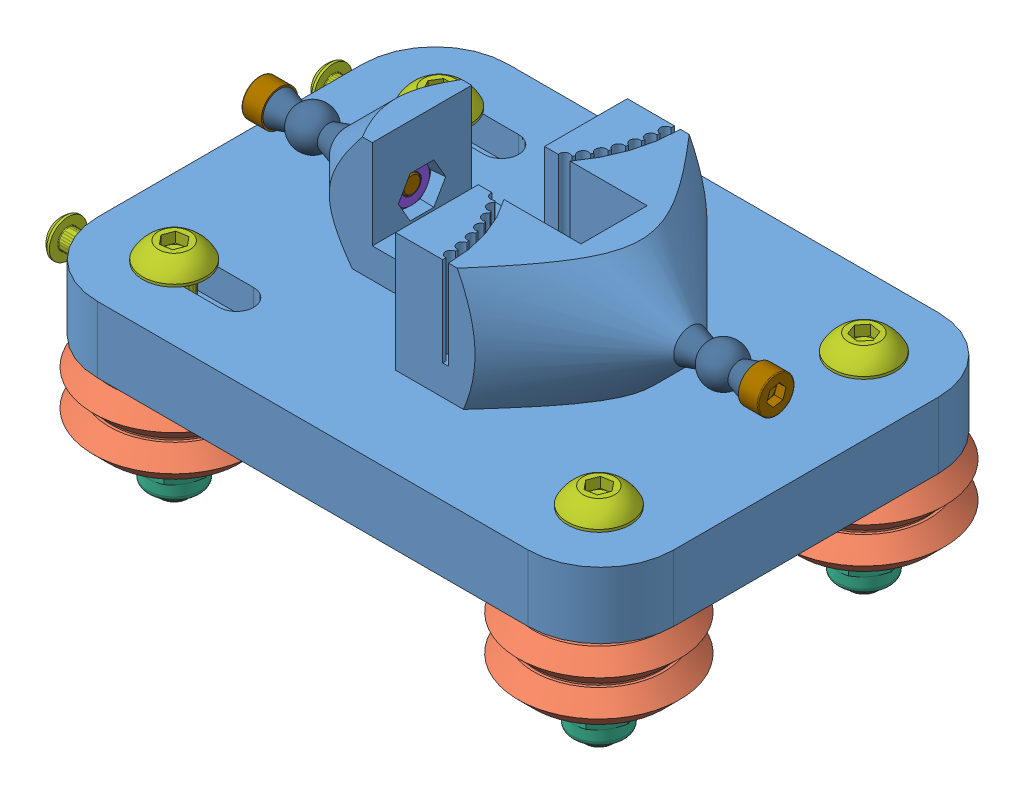
SolidWorks assembly Carriage, configuration Default. Lengths in mm.
Overall size (98.62 48 70.21).
43 component instances, 10 part files, 52 mates.
Components (placement in the parent):
- Carriage Plate-1: Carriage Plate [Default] at (-68.6928 -3.4221 37.1074) size (87 28 62)
- Dual V Wheel Assy-1: Dual V Wheel Assy [Default] at (-5.296 -57.3171 -30.5998) x (0 -1 0) z (0.099606 0 0.995027) size (17.35 24.39 24.39)
  - Dual V Wheel-1: Dual V Wheel [Default] at (-47.445 10.5779 17.8496) size (10.23 24.39 24.39)
  - 625 2RS-1: 625 2RS [Default] at (-46.945 10.5779 17.8496) x (0 0 1) z (-1 0 0) size (16 16 5)
  - 625 2RS-2: 625 2RS [Default] at (-52.945 10.5779 17.8496) x (0 -0.999394 0.034809) z (-1 0 0) size (16 16 5)
  - Precision Shim-1: Precision Shim [Default] at (-47.445 10.5779 17.8496) size (1 7.7 7.7)
  - Quarter Inch washer-1: Quarter Inch washer [Default] at (-56.12 10.5779 17.8496) x (1 0 0) z (0 -0.459208 0.888329) size (6.35 8 8)
- Dual V Wheel Assy-2: Dual V Wheel Assy [Default] at (16.2723 -57.3171 7.5423) x (0 -1 0) z (-0.840315 0 0.542098) size (17.35 24.39 24.39)
  - Dual V Wheel-1: Dual V Wheel [Default] at (-47.445 10.5779 17.8496) size (10.23 24.39 24.39)
  - 625 2RS-1: 625 2RS [Default] at (-46.945 10.5779 17.8496) x (0 0 1) z (-1 0 0) size (16 16 5)
  - 625 2RS-2: 625 2RS [Default] at (-52.945 10.5779 17.8496) x (0 -0.999394 0.034809) z (-1 0 0) size (16 16 5)
  - Precision Shim-1: Precision Shim [Default] at (-47.445 10.5779 17.8496) size (1 7.7 7.7)
  - Quarter Inch washer-1: Quarter Inch washer [Default] at (-56.12 10.5779 17.8496) x (1 0 0) z (0 -0.459208 0.888329) size (6.35 8 8)
- Dual V Wheel Assy-3: Dual V Wheel Assy [Default] at (-72.4169 -57.3171 40.1065) x (0 -1 0) z (0.978939 0 -0.204151) size (17.35 24.39 24.39)
  - Dual V Wheel-1: Dual V Wheel [Default] at (-47.445 10.5779 17.8496) size (10.23 24.39 24.39)
  - 625 2RS-1: 625 2RS [Default] at (-46.945 10.5779 17.8496) x (0 0 1) z (-1 0 0) size (16 16 5)
  - 625 2RS-2: 625 2RS [Default] at (-52.945 10.5779 17.8496) x (0 -0.999394 0.034809) z (-1 0 0) size (16 16 5)
  - Precision Shim-1: Precision Shim [Default] at (-47.445 10.5779 17.8496) size (1 7.7 7.7)
  - Quarter Inch washer-1: Quarter Inch washer [Default] at (-56.12 10.5779 17.8496) x (1 0 0) z (0 -0.459208 0.888329) size (6.35 8 8)
- Dual V Wheel Assy-4: Dual V Wheel Assy [Default] at (-68.5718 -57.3171 -31.1832) x (0 -1 0) z (0.050683 0 0.998715) size (17.35 24.39 24.39)
  - Dual V Wheel-1: Dual V Wheel [Default] at (-47.445 10.5779 17.8496) size (10.23 24.39 24.39)
  - 625 2RS-1: 625 2RS [Default] at (-46.945 10.5779 17.8496) x (0 0 1) z (-1 0 0) size (16 16 5)
  - 625 2RS-2: 625 2RS [Default] at (-52.945 10.5779 17.8496) x (0 -0.999394 0.034809) z (-1 0 0) size (16 16 5)
  - Precision Shim-1: Precision Shim [Default] at (-47.445 10.5779 17.8496) size (1 7.7 7.7)
  - Quarter Inch washer-1: Quarter Inch washer [Default] at (-56.12 10.5779 17.8496) x (1 0 0) z (0 -0.459208 0.888329) size (6.35 8 8)
- torque nut 01_iso-1: torque nut 01_iso [ISO 7040-M5-C] at (-57.1028 -19.7721 26.1074) x (0.027758 0 0.999615) z (0 -1 0) size (8 9.24 6.8)
- socket button head screw_iso-2: socket button head screw_iso [ISO 7380 - M5 x 30 --- 30C] at (-57.1028 9.3279 26.1074) x (0 -1 0) z (0.169605 0 0.985512) size (32.75 9.5 9.5)
- socket button head screw_iso-3: socket button head screw_iso [ISO 7380 - M5 x 30 --- 30C] at (7.0072 9.3279 26.1074) x (0 -1 0) z (-0.775954 0 0.63079) size (32.75 9.5 9.5)
- socket button head screw_iso-4: socket button head screw_iso [ISO 7380 - M5 x 30 --- 30C] at (7.0072 9.3279 -13.8926) x (0 -1 0) z (-0.770259 0 -0.637731) size (32.75 9.5 9.5)
- socket button head screw_iso-5: socket button head screw_iso [ISO 7380 - M5 x 30 --- 30C] at (-57.1028 9.3279 -13.8926) x (0 -1 0) z (-0.853361 0 -0.52132) size (32.75 9.5 9.5)
- torque nut 01_iso-2: torque nut 01_iso [ISO 7040-M5-C] at (7.0072 -19.7721 26.1074) x (-0.044821 0 0.998995) z (0 -1 0) size (8 9.24 6.8)
- torque nut 01_iso-3: torque nut 01_iso [ISO 7040-M5-C] at (7.0072 -19.7721 -13.8926) x (-0.103086 0 0.994672) z (0 -1 0) size (8 9.24 6.8)
- torque nut 01_iso-4: torque nut 01_iso [ISO 7040-M5-C] at (-57.1028 -19.7721 -13.8926) x (-0.974294 0 -0.225282) z (0 -1 0) size (8 9.24 6.8)
- socket button head screw_iso-6: socket button head screw_iso [ISO 7380 - M3 x 12 --- 12C] at (-74.7528 1.5779 26.1074) x (1 0 0) z (0 0.980313 0.197449) size (13.65 5.7 5.7)
- torque nut 01_iso-5: torque nut 01_iso [ISO 7040-M3-C] at (-63.5428 1.5779 26.1074) x (0 -0.866025 -0.5) z (1 0 0) size (5.5 6.35 4.5)
- socket button head screw_iso-7: socket button head screw_iso [ISO 7380 - M3 x 12 --- 12C] at (-74.7528 1.5779 -13.8926) x (1 0 0) z (0 0.265442 0.964127) size (13.65 5.7 5.7)
- torque nut 01_iso-6: torque nut 01_iso [ISO 7040-M3-C] at (-63.5428 1.5779 -13.8926) x (0 -0.866025 0.5) z (1 0 0) size (5.5 6.35 4.5)
- hex nut style 1 gradeab_iso-1: hex nut style 1 gradeab_iso [Hexagon Nut ISO - 4032 - M3 - D - C] at (-9.0928 14.5779 6.1074) x (0 -0.5 0.866025) z (-1 0 0) size (5.5 6.35 2.4)
- socket head cap screw_iso-1: socket head cap screw_iso [ISO 4762 M3 x 20 --- 20C] at (13.8072 14.5779 6.1074) x (-1 0 0) z (0 -0.980465 -0.196695) size (23 5.5 5.5)
- Traxxas Ball-1: Traxxas Ball [Default] at (0.8072 14.5779 6.1074) x (0 -1 0) z (0 0 1) size (6 10 6)
- Traxxas Ball-2: Traxxas Ball [Default] at (-61.1928 14.5779 6.1074) x (0 -1 0) z (0 0 1) size (6 10 6)
- socket head cap screw_iso-2: socket head cap screw_iso [ISO 4762 M3 x 20 --- 20C] at (-64.1928 14.5779 6.1074) x (1 0 0) z (0 -0.973692 0.227866) size (23 5.5 5.5)
- hex nut style 1 gradeab_iso-2: hex nut style 1 gradeab_iso [Hexagon Nut ISO - 4032 - M3 - D - C] at (-43.6928 14.5779 6.1074) x (0 -0.5 0.866025) z (-1 0 0) size (5.5 6.35 2.4)
Mates (geometry in assembly coordinates):
- Concentric1: concentric aligned: cylinder of Carriage Plate-1 through (7.0072 1.9779 -13.8926) axis (0 -1 0) radius 4.1; cylinder of Dual V Wheel Assy-1/Quarter Inch washer-1 through (7.0072 -1.1971 -13.8926) axis (0 -1 0) radius 4
- Distance1: distance = 0.3 mm anti-aligned: plane of Carriage Plate-1 through (-68.6928 1.6779 37.1074) normal (0 -1 0); plane of Dual V Wheel Assy-1/Quarter Inch washer-1 through (10.7259 1.9779 -12.4189) normal (0 1 0)
- Concentric2: concentric aligned: cylinder of Carriage Plate-1 through (7.0072 1.9779 26.1074) axis (0 -1 0) radius 4.1; cylinder of Dual V Wheel Assy-2/Quarter Inch washer-1 through (7.0072 -1.1971 26.1074) axis (0 -1 0) radius 4
- Distance2: distance = 0.3 mm anti-aligned: plane of Carriage Plate-1 through (-68.6928 1.6779 37.1074) normal (0 -1 0); plane of Dual V Wheel Assy-2/Quarter Inch washer-1 through (7.39 1.9779 30.089) normal (0 1 0)
- Distance6: distance = 0.1 mm anti-aligned: plane of Carriage Plate-1 through (-47.6928 1.9779 22.0074) normal (0 0 1); cylinder of Dual V Wheel Assy-3/Quarter Inch washer-1 through (-57.1028 -1.1971 26.1074) axis (0 -1 0) radius 4
- Distance3: distance = 0.3 mm anti-aligned: plane of Dual V Wheel Assy-3/Quarter Inch washer-1 through (-56.03 1.9779 22.2539) normal (0 1 0); plane of Carriage Plate-1 through (-68.6928 1.6779 37.1074) normal (0 -1 0)
- LimitDistance1: limit distance = 4.59 mm anti-aligned: cylinder of Dual V Wheel Assy-3/Quarter Inch washer-1 through (-57.1028 -1.1971 26.1074) axis (0 -1 0) radius 4; plane of Carriage Plate-1 through (-65.6928 1.9779 23.3574) normal (1 0 0)
- Distance7: distance = 0.1 mm anti-aligned: cylinder of Dual V Wheel Assy-4/Quarter Inch washer-1 through (-57.1028 -1.1971 -13.8926) axis (0 -1 0) radius 4; plane of Carriage Plate-1 through (-58.6928 1.9779 -9.7926) normal (0 0 -1)
- Distance8: distance = 0.3 mm anti-aligned: plane of Dual V Wheel Assy-4/Quarter Inch washer-1 through (-53.4609 1.9779 -12.2382) normal (0 1 0); plane of Carriage Plate-1 through (-68.6928 1.6779 37.1074) normal (0 -1 0)
- LimitDistance2: limit distance = 4.59 mm anti-aligned: cylinder of Dual V Wheel Assy-4/Quarter Inch washer-1 through (-57.1028 -1.1971 -13.8926) axis (0 -1 0) radius 4; plane of Carriage Plate-1 through (-65.6928 1.9779 -16.6426) normal (1 0 0)
- Coincident6: coincident anti-aligned: plane of Dual V Wheel Assy-3/625 2RS-1 through (-57.6438 -15.3721 23.5132) normal (0 -1 0); plane of torque nut 01_iso-1 through (-61.7198 -15.3721 26.2356) normal (0 1 0)
- Concentric7: concentric anti-aligned: cylinder of Dual V Wheel Assy-3/625 2RS-1 through (-57.1028 -10.3721 26.1074) axis (0 -1 0) radius 2.5; cylinder of socket button head screw_iso-2 through (-57.1028 9.3279 26.1074) axis (0 1 0) radius 2.5
- Coincident7: coincident anti-aligned: plane of Carriage Plate-1 through (7.3072 6.5779 -13.8926) normal (0 1 0); plane of socket button head screw_iso-2 through (-54.639 6.5779 25.6834) normal (0 -1 0)
- Concentric8: concentric anti-aligned: cylinder of torque nut 01_iso-1 through (-57.1028 -15.3721 26.1074) axis (0 -1 0) radius 2.1; cylinder of socket button head screw_iso-2 through (-57.1028 9.3279 26.1074) axis (0 1 0) radius 2.5
- Concentric9: concentric anti-aligned: cylinder of Dual V Wheel Assy-2/625 2RS-1 through (7.0072 -10.3721 26.1074) axis (0 -1 0) radius 2.5; cylinder of socket button head screw_iso-3 through (7.0072 9.3279 26.1074) axis (0 1 0) radius 2.5
- Concentric10: concentric anti-aligned: cylinder of socket button head screw_iso-3 through (7.0072 9.3279 26.1074) axis (0 1 0) radius 2.5; cylinder of torque nut 01_iso-2 through (7.0072 -15.3721 26.1074) axis (0 -1 0) radius 2.1
- Concentric11: concentric anti-aligned: cylinder of Dual V Wheel Assy-1/625 2RS-1 through (7.0072 -10.3721 -13.8926) axis (0 -1 0) radius 2.5; cylinder of socket button head screw_iso-4 through (7.0072 9.3279 -13.8926) axis (0 1 0) radius 2.5
- Concentric12: concentric anti-aligned: cylinder of socket button head screw_iso-4 through (7.0072 9.3279 -13.8926) axis (0 1 0) radius 2.5; cylinder of torque nut 01_iso-3 through (7.0072 -15.3721 -13.8926) axis (0 -1 0) radius 2.1
- Concentric13: concentric anti-aligned: cylinder of Dual V Wheel Assy-4/625 2RS-1 through (-57.1028 -10.3721 -13.8926) axis (0 -1 0) radius 2.5; cylinder of socket button head screw_iso-5 through (-57.1028 9.3279 -13.8926) axis (0 1 0) radius 2.5
- Concentric14: concentric anti-aligned: cylinder of socket button head screw_iso-5 through (-57.1028 9.3279 -13.8926) axis (0 1 0) radius 2.5; cylinder of torque nut 01_iso-4 through (-57.1028 -15.3721 -13.8926) axis (0 -1 0) radius 2.1
- Coincident8: coincident anti-aligned: plane of Carriage Plate-1 through (7.3072 6.5779 -13.8926) normal (0 1 0); plane of socket button head screw_iso-3 through (8.5842 6.5779 28.0473) normal (0 -1 0)
- Coincident9: coincident anti-aligned: plane of Carriage Plate-1 through (7.3072 6.5779 -13.8926) normal (0 1 0); plane of socket button head screw_iso-4 through (5.4129 6.5779 -11.967) normal (0 -1 0)
- Coincident10: coincident anti-aligned: plane of Carriage Plate-1 through (7.3072 6.5779 -13.8926) normal (0 1 0); plane of socket button head screw_iso-5 through (-58.4061 6.5779 -11.7592) normal (0 -1 0)
- Coincident11: coincident anti-aligned: plane of Dual V Wheel Assy-2/625 2RS-1 through (8.4438 -15.3721 28.3342) normal (0 -1 0); plane of torque nut 01_iso-2 through (2.3931 -15.3721 25.9004) normal (0 1 0)
- Coincident12: coincident anti-aligned: plane of Dual V Wheel Assy-1/625 2RS-1 through (9.6441 -15.3721 -14.1566) normal (0 -1 0); plane of torque nut 01_iso-3 through (2.4131 -15.3721 -14.3687) normal (0 1 0)
- Coincident13: coincident anti-aligned: plane of Dual V Wheel Assy-4/625 2RS-1 through (-54.4562 -15.3721 -14.0269) normal (0 -1 0); plane of torque nut 01_iso-4 through (-56.0622 -15.3721 -18.3927) normal (0 1 0)
- Concentric15: concentric aligned: cylinder of Carriage Plate-1 through (18.3082 1.5779 26.1074) axis (-1 0 0) radius 1.6; cylinder of socket button head screw_iso-6 through (-74.7528 1.5779 26.1074) axis (-1 0 0) radius 1.5
- LimitDistance3: limit distance = 4.41 mm anti-aligned: plane of socket button head screw_iso-6 through (-73.1028 1.8741 24.6369) normal (1 0 0); plane of Carriage Plate-1 through (-68.6928 6.5779 26.1074) normal (-1 0 0)
- Concentric16: concentric anti-aligned: cylinder of socket button head screw_iso-6 through (-74.7528 1.5779 26.1074) axis (-1 0 0) radius 1.5; cylinder of torque nut 01_iso-5 through (-65.6928 1.5779 26.1074) axis (1 0 0) radius 1.25
- Coincident15: coincident anti-aligned: plane of Carriage Plate-1 through (-65.6928 1.9779 23.3574) normal (1 0 0); plane of torque nut 01_iso-5 through (-65.6928 3.1656 23.3574) normal (-1 0 0)
- Coincident16: coincident anti-aligned: plane of Carriage Plate-1 through (-65.6928 1.9779 28.8574) normal (0 0 -1); plane of torque nut 01_iso-5 through (-65.6928 3.1656 28.8574) normal (0 0 1)
- Concentric171: concentric aligned: cylinder of Carriage Plate-1 through (18.3082 1.5779 -13.8926) axis (-1 0 0) radius 1.6; cylinder of socket button head screw_iso-7 through (-74.7528 1.5779 -13.8926) axis (-1 0 0) radius 2.85
- LimitDistance4: limit distance = 4.41 mm anti-aligned: plane of Carriage Plate-1 through (-68.6928 6.5779 26.1074) normal (-1 0 0); plane of socket button head screw_iso-7 through (-73.1028 3.0241 -14.2908) normal (1 0 0)
- Concentric18: concentric anti-aligned: cylinder of socket button head screw_iso-7 through (-74.7528 1.5779 -13.8926) axis (-1 0 0) radius 1.5; cylinder of torque nut 01_iso-6 through (-65.6928 1.5779 -13.8926) axis (1 0 0) radius 1.25
- Coincident18: coincident anti-aligned: plane of Carriage Plate-1 through (-65.6928 1.9779 -11.1426) normal (0 0 -1); plane of torque nut 01_iso-6 through (-65.6928 3.1656 -11.1426) normal (0 0 1)
- Coincident19: coincident anti-aligned: plane of Carriage Plate-1 through (-65.6928 1.9779 -16.6426) normal (1 0 0); plane of torque nut 01_iso-6 through (-65.6928 -0.0098 -16.6426) normal (-1 0 0)
- Tangent5: tangent anti-aligned: cylinder of Dual V Wheel Assy-3/Quarter Inch washer-1 through (-57.1028 -1.1971 26.1074) axis (0 -1 0) radius 4; plane of socket button head screw_iso-6 through (-61.1028 1.5779 26.1074) normal (1 0 0)
- Tangent6: tangent anti-aligned: cylinder of Dual V Wheel Assy-4/Quarter Inch washer-1 through (-57.1028 -1.1971 -13.8926) axis (0 -1 0) radius 4; plane of socket button head screw_iso-7 through (-61.1028 1.5779 -13.8926) normal (1 0 0)
- Concentric172: concentric anti-aligned: cylinder of Carriage Plate-1 through (-68.6938 14.5779 6.1074) axis (1 0 0) radius 1.825; cylinder of Traxxas Ball-1 through (0.8072 14.5779 6.1074) axis (-1 0 0) radius 1.5
- Coincident20: coincident anti-aligned: plane of Carriage Plate-1 through (0.8072 24.5779 13.6074) normal (1 0 0); plane of Traxxas Ball-1 through (0.8072 12.0779 6.1074) normal (-1 0 0)
- Concentric173: concentric aligned: cylinder of Carriage Plate-1 through (-68.6938 14.5779 6.1074) axis (1 0 0) radius 1.825; cylinder of socket head cap screw_iso-1 through (45.5572 14.5779 6.1074) axis (1 0 0) radius 1.5
- Coincident21: coincident anti-aligned: plane of socket head cap screw_iso-1 through (10.8072 15.1188 3.4111) normal (-1 0 0); plane of Traxxas Ball-1 through (10.8072 13.0779 6.1074) normal (1 0 0)
- Concentric174: concentric anti-aligned: cylinder of hex nut style 1 gradeab_iso-1 through (-6.6928 14.5779 6.1074) axis (-1 0 0) radius 1.25; cylinder of socket head cap screw_iso-1 through (45.5572 14.5779 6.1074) axis (1 0 0) radius 1.5
- Parallel1: parallel: line of Carriage Plate-1 through (-10.6928 17.6779 4.3176) axis (0 0 1); plane of hex nut style 1 gradeab_iso-1 through (-6.6928 17.3279 7.6951) normal (0 1 0)
- Coincident23: coincident anti-aligned: plane of Carriage Plate-1 through (-6.6928 -3.4221 37.1074) normal (-1 0 0); plane of hex nut style 1 gradeab_iso-1 through (-6.6928 17.3279 7.6951) normal (1 0 0)
- Concentric175: concentric aligned: cylinder of Carriage Plate-1 through (18.3082 14.5779 6.1074) axis (-1 0 0) radius 1.825; cylinder of Traxxas Ball-2 through (-61.1928 14.5779 6.1074) axis (-1 0 0) radius 1.5
- Coincident24: coincident anti-aligned: plane of Carriage Plate-1 through (-51.1928 24.5779 13.6074) normal (-1 0 0); plane of Traxxas Ball-2 through (-51.1928 13.0779 6.1074) normal (1 0 0)
- Concentric176: concentric aligned: cylinder of Carriage Plate-1 through (18.3082 14.5779 6.1074) axis (-1 0 0) radius 1.825; cylinder of socket head cap screw_iso-2 through (-95.9428 14.5779 6.1074) axis (-1 0 0) radius 1.5
- Coincident25: coincident anti-aligned: plane of Traxxas Ball-2 through (-61.1928 12.0779 6.1074) normal (-1 0 0); plane of socket head cap screw_iso-2 through (-61.1928 15.2046 8.785) normal (1 0 0)
- Concentric177: concentric aligned: cylinder of socket head cap screw_iso-2 through (-95.9428 14.5779 6.1074) axis (-1 0 0) radius 1.5; cylinder of hex nut style 1 gradeab_iso-2 through (-41.2928 14.5779 6.1074) axis (-1 0 0) radius 1.25
- Parallel2: parallel: line of Carriage Plate-1 through (-39.6928 17.6779 4.3176) axis (0 0 1); plane of hex nut style 1 gradeab_iso-2 through (-41.2928 17.3279 7.6951) normal (0 1 0)
- Coincident27: coincident anti-aligned: plane of Carriage Plate-1 through (-43.6928 -3.4221 37.1074) normal (1 0 0); plane of hex nut style 1 gradeab_iso-2 through (-43.6928 17.3279 7.6951) normal (-1 0 0)
